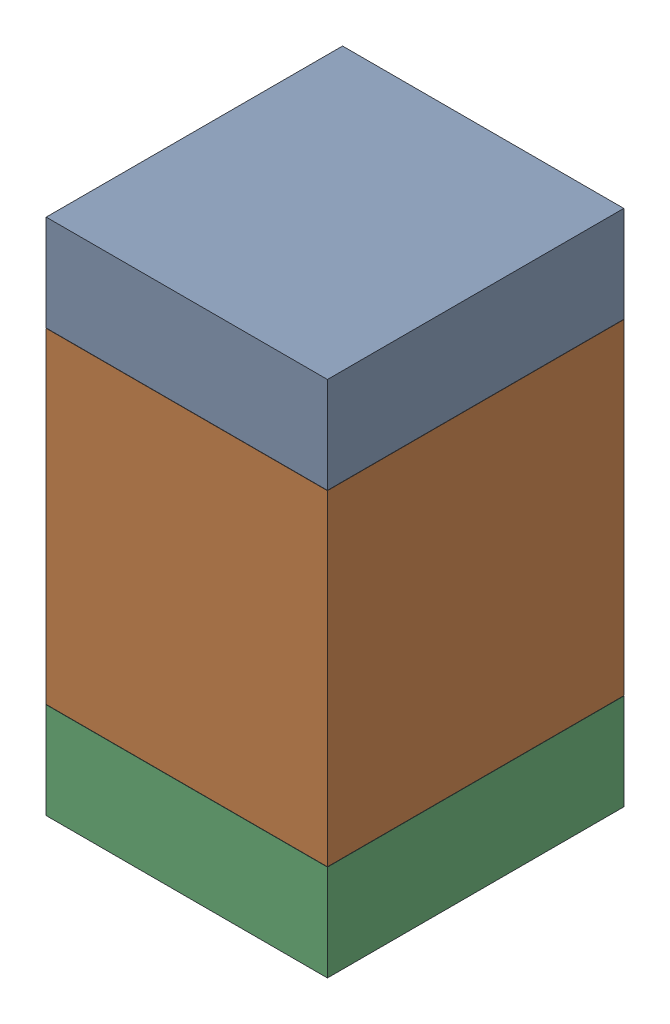
SolidWorks assembly R18, configuration Default. Lengths in mm.
Overall size (0.95 1.75 1).
6 component instances, 2 part files, 0 mates.
Components (placement in the parent):
- 6575495072-1: 6575495072 [Default] at (11.049 12.3965 0) size (0.95 0.32 1)
  - Extruded_6-1: Extruded_6 [Default] at origin size (0.95 0.32 1)
- 6575494912-1: 6575494912 [Default] at (11.049 11.684 0) size (0.95 1.1 1)
  - Extruded_7-1: Extruded_7 [Default] at origin size (0.95 1.1 1)
- 6575495072-2: 6575495072 [Default] at (11.049 10.9715 0) size (0.95 0.32 1)
  - Extruded_6-1: Extruded_6 [Default] at origin size (0.95 0.32 1)
